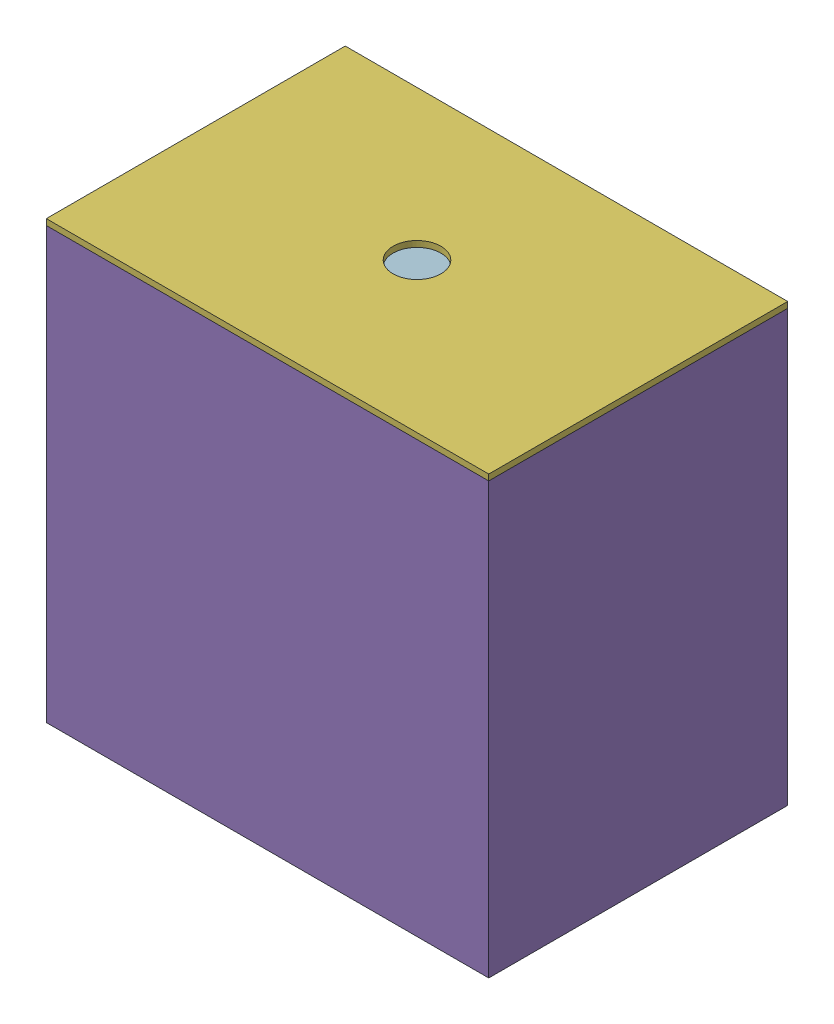
SolidWorks assembly Drying Racks Inside Chamber v1, configuration Default. Lengths in mm.
Overall size (469.9 463.55 317.5).
65 component instances, 6 part files, 6 mates.
Components (placement in the parent):
- Stacked Tray Assembly-1: Stacked Tray Assembly [Default] at (-61.8185 38.0151 -6.3555) size (406.4 115.52 254)
  - Bottom Tray Assembly-1: Bottom Tray Assembly [Default] at (173.9076 -76.6729 -13.7937) size (406.4 76.81 254)
    - Perforated Tray-1: Perforated Tray [92725T36] at (-209.6714 56.3674 72.3455) size (406.4 0.61 254)
    - Tray Base-1: Tray Base [89825K319] at (-406.5214 -13.7874 72.3455) size (12.7 12.7 254)
    - Tray Base-2: Tray Base [89825K319] at (-12.8214 -13.7874 72.3455) size (12.7 12.7 254)
    - Tray Sides-1: Tray Sides [89825K319] at (-12.8214 24.3126 192.9955) x (1 0 0) z (0 -1 0) size (12.7 12.7 63.5)
    - Tray Sides-2: Tray Sides [89825K319] at (-406.5214 24.3126 192.9955) x (1 0 0) z (0 -1 0) size (12.7 12.7 63.5)
    - Tray Sides-3: Tray Sides [89825K319] at (-12.8214 24.3126 -48.3045) x (1 0 0) z (0 -1 0) size (12.7 12.7 63.5)
    - Tray Sides-4: Tray Sides [89825K319] at (-406.5214 24.3126 -48.3045) x (1 0 0) z (0 -1 0) size (12.7 12.7 63.5)
  - Additional Tray Assembly-1: Additional Tray Assembly [Default] at (65.2935 16.9544 6.2103) size (406.4 38.71 254)
    - Perforated Tray-1: Perforated Tray [92725T36] at (-101.0573 1.4498 52.3416) size (406.4 0.61 254)
    - Additional Tray Legs-1: Additional Tray Legs [8457K25] at (-299.4948 -17.905 174.5791) x (1 0 0) z (0 1 0) size (9.53 9.53 38.1)
    - Additional Tray Legs-2: Additional Tray Legs [8457K25] at (97.3802 -17.905 174.5791) x (1 0 0) z (0 1 0) size (9.53 9.53 38.1)
    - Additional Tray Legs-3: Additional Tray Legs [8457K25] at (-299.4948 -17.905 -69.8959) x (1 0 0) z (0 1 0) size (9.53 9.53 38.1)
    - Additional Tray Legs-4: Additional Tray Legs [8457K25] at (97.3802 -17.905 -69.8959) x (1 0 0) z (0 1 0) size (9.53 9.53 38.1)
  - Additional Tray Assembly-7: Additional Tray Assembly [Default] at (65.2935 55.0544 6.2103) size (406.4 38.71 254)
    - Perforated Tray-1: Perforated Tray [92725T36] at (-101.0573 1.4498 52.3416) size (406.4 0.61 254)
    - Additional Tray Legs-1: Additional Tray Legs [8457K25] at (-299.4948 -17.905 174.5791) x (1 0 0) z (0 1 0) size (9.53 9.53 38.1)
    - Additional Tray Legs-2: Additional Tray Legs [8457K25] at (97.3802 -17.905 174.5791) x (1 0 0) z (0 1 0) size (9.53 9.53 38.1)
    - Additional Tray Legs-3: Additional Tray Legs [8457K25] at (-299.4948 -17.905 -69.8959) x (1 0 0) z (0 1 0) size (9.53 9.53 38.1)
    - Additional Tray Legs-4: Additional Tray Legs [8457K25] at (97.3802 -17.905 -69.8959) x (1 0 0) z (0 1 0) size (9.53 9.53 38.1)
  - Additional Tray Assembly-8: Additional Tray Assembly [Default] at (65.2935 93.1544 6.2103) size (406.4 38.71 254)
    - Perforated Tray-1: Perforated Tray [92725T36] at (-101.0573 1.4498 52.3416) size (406.4 0.61 254)
    - Additional Tray Legs-1: Additional Tray Legs [8457K25] at (-299.4948 -17.905 174.5791) x (1 0 0) z (0 1 0) size (9.53 9.53 38.1)
    - Additional Tray Legs-2: Additional Tray Legs [8457K25] at (97.3802 -17.905 174.5791) x (1 0 0) z (0 1 0) size (9.53 9.53 38.1)
    - Additional Tray Legs-3: Additional Tray Legs [8457K25] at (-299.4948 -17.905 -69.8959) x (1 0 0) z (0 1 0) size (9.53 9.53 38.1)
    - Additional Tray Legs-4: Additional Tray Legs [8457K25] at (97.3802 -17.905 -69.8959) x (1 0 0) z (0 1 0) size (9.53 9.53 38.1)
  - Additional Tray Assembly-9: Additional Tray Assembly [Default] at (65.2935 131.2544 6.2103) size (406.4 38.71 254)
    - Perforated Tray-1: Perforated Tray [92725T36] at (-101.0573 1.4498 52.3416) size (406.4 0.61 254)
    - Additional Tray Legs-1: Additional Tray Legs [8457K25] at (-299.4948 -17.905 174.5791) x (1 0 0) z (0 1 0) size (9.53 9.53 38.1)
    - Additional Tray Legs-2: Additional Tray Legs [8457K25] at (97.3802 -17.905 174.5791) x (1 0 0) z (0 1 0) size (9.53 9.53 38.1)
    - Additional Tray Legs-3: Additional Tray Legs [8457K25] at (-299.4948 -17.905 -69.8959) x (1 0 0) z (0 1 0) size (9.53 9.53 38.1)
    - Additional Tray Legs-4: Additional Tray Legs [8457K25] at (97.3802 -17.905 -69.8959) x (1 0 0) z (0 1 0) size (9.53 9.53 38.1)
  - Additional Tray Assembly-10: Additional Tray Assembly [Default] at (65.2935 169.3544 6.2103) size (406.4 38.71 254)
    - Perforated Tray-1: Perforated Tray [92725T36] at (-101.0573 1.4498 52.3416) size (406.4 0.61 254)
    - Additional Tray Legs-1: Additional Tray Legs [8457K25] at (-299.4948 -17.905 174.5791) x (1 0 0) z (0 1 0) size (9.53 9.53 38.1)
    - Additional Tray Legs-2: Additional Tray Legs [8457K25] at (97.3802 -17.905 174.5791) x (1 0 0) z (0 1 0) size (9.53 9.53 38.1)
    - Additional Tray Legs-3: Additional Tray Legs [8457K25] at (-299.4948 -17.905 -69.8959) x (1 0 0) z (0 1 0) size (9.53 9.53 38.1)
    - Additional Tray Legs-4: Additional Tray Legs [8457K25] at (97.3802 -17.905 -69.8959) x (1 0 0) z (0 1 0) size (9.53 9.53 38.1)
  - Additional Tray Assembly-11: Additional Tray Assembly [Default] at (65.2935 207.4544 6.2103) size (406.4 38.71 254)
    - Perforated Tray-1: Perforated Tray [92725T36] at (-101.0573 1.4498 52.3416) size (406.4 0.61 254)
    - Additional Tray Legs-1: Additional Tray Legs [8457K25] at (-299.4948 -17.905 174.5791) x (1 0 0) z (0 1 0) size (9.53 9.53 38.1)
    - Additional Tray Legs-2: Additional Tray Legs [8457K25] at (97.3802 -17.905 174.5791) x (1 0 0) z (0 1 0) size (9.53 9.53 38.1)
    - Additional Tray Legs-3: Additional Tray Legs [8457K25] at (-299.4948 -17.905 -69.8959) x (1 0 0) z (0 1 0) size (9.53 9.53 38.1)
    - Additional Tray Legs-4: Additional Tray Legs [8457K25] at (97.3802 -17.905 -69.8959) x (1 0 0) z (0 1 0) size (9.53 9.53 38.1)
  - Additional Tray Assembly-12: Additional Tray Assembly [Default] at (65.2935 245.5544 6.2103) size (406.4 38.71 254)
    - Perforated Tray-1: Perforated Tray [92725T36] at (-101.0573 1.4498 52.3416) size (406.4 0.61 254)
    - Additional Tray Legs-1: Additional Tray Legs [8457K25] at (-299.4948 -17.905 174.5791) x (1 0 0) z (0 1 0) size (9.53 9.53 38.1)
    - Additional Tray Legs-2: Additional Tray Legs [8457K25] at (97.3802 -17.905 174.5791) x (1 0 0) z (0 1 0) size (9.53 9.53 38.1)
    - Additional Tray Legs-3: Additional Tray Legs [8457K25] at (-299.4948 -17.905 -69.8959) x (1 0 0) z (0 1 0) size (9.53 9.53 38.1)
    - Additional Tray Legs-4: Additional Tray Legs [8457K25] at (97.3802 -17.905 -69.8959) x (1 0 0) z (0 1 0) size (9.53 9.53 38.1)
  - Additional Tray Assembly-13: Additional Tray Assembly [Default] at (65.2935 283.6544 6.2103) size (406.4 38.71 254)
    - Perforated Tray-1: Perforated Tray [92725T36] at (-101.0573 1.4498 52.3416) size (406.4 0.61 254)
    - Additional Tray Legs-1: Additional Tray Legs [8457K25] at (-299.4948 -17.905 174.5791) x (1 0 0) z (0 1 0) size (9.53 9.53 38.1)
    - Additional Tray Legs-2: Additional Tray Legs [8457K25] at (97.3802 -17.905 174.5791) x (1 0 0) z (0 1 0) size (9.53 9.53 38.1)
    - Additional Tray Legs-3: Additional Tray Legs [8457K25] at (-299.4948 -17.905 -69.8959) x (1 0 0) z (0 1 0) size (9.53 9.53 38.1)
    - Additional Tray Legs-4: Additional Tray Legs [8457K25] at (97.3802 -17.905 -69.8959) x (1 0 0) z (0 1 0) size (9.53 9.53 38.1)
  - Additional Tray Assembly-14: Additional Tray Assembly [Default] at (65.2935 321.7544 6.2103) size (406.4 38.71 254)
    - Perforated Tray-1: Perforated Tray [92725T36] at (-101.0573 1.4498 52.3416) size (406.4 0.61 254)
    - Additional Tray Legs-1: Additional Tray Legs [8457K25] at (-299.4948 -17.905 174.5791) x (1 0 0) z (0 1 0) size (9.53 9.53 38.1)
    - Additional Tray Legs-2: Additional Tray Legs [8457K25] at (97.3802 -17.905 174.5791) x (1 0 0) z (0 1 0) size (9.53 9.53 38.1)
    - Additional Tray Legs-3: Additional Tray Legs [8457K25] at (-299.4948 -17.905 -69.8959) x (1 0 0) z (0 1 0) size (9.53 9.53 38.1)
    - Additional Tray Legs-4: Additional Tray Legs [8457K25] at (97.3802 -17.905 -69.8959) x (1 0 0) z (0 1 0) size (9.53 9.53 38.1)
- Drying Chamber-1: Drying Chamber [Default] at (-326.1823 -65.1452 204.5964) x (1 0 0) z (0 1 0) size (469.9 317.5 457.2)
- Drying Chamber Roof-1: Drying Chamber Roof [Default] at (-332.5323 392.0548 210.9464) size (469.9 6.35 317.5)
Mates (geometry in assembly coordinates):
- Coincident1: coincident anti-aligned: plane of Stacked Tray Assembly-1/Bottom Tray Assembly-1/Tray Base-2 through (103.5539 -58.7952 179.1964) normal (0 -1 0); plane of Drying Chamber-1 through (-326.1823 -58.7952 204.5964) normal (0 1 0)
- Distance1: distance = 25.4 mm anti-aligned: plane of Stacked Tray Assembly-1/Bottom Tray Assembly-1/Tray Sides-2 through (-290.1461 -46.0952 179.1964) normal (0 0 1); plane of Drying Chamber-1 through (-326.1823 -65.1452 204.5964) normal (0 0 -1)
- Distance2: distance = 25.4 mm anti-aligned: plane of Drying Chamber-1 through (-326.1823 -65.1452 204.5964) normal (1 0 0); plane of Stacked Tray Assembly-1/Bottom Tray Assembly-1/Tray Sides-2 through (-300.7823 -46.0952 168.5601) normal (-1 0 0)
- Coincident5: coincident anti-aligned: plane of Drying Chamber-1 through (137.3677 392.0548 204.5964) normal (0 1 0); plane of Drying Chamber Roof-1 through (-332.5323 392.0548 210.9464) normal (0 -1 0)
- Coincident6: coincident aligned: plane of Drying Chamber-1 through (137.3677 -65.1452 204.5964) normal (1 0 0); plane of Drying Chamber Roof-1 through (137.3677 398.4048 210.9464) normal (1 0 0)
- Coincident7: coincident aligned: plane of Drying Chamber-1 through (-326.1823 -65.1452 210.9464) normal (0 0 1); plane of Drying Chamber Roof-1 through (-332.5323 398.4048 210.9464) normal (0 0 1)
